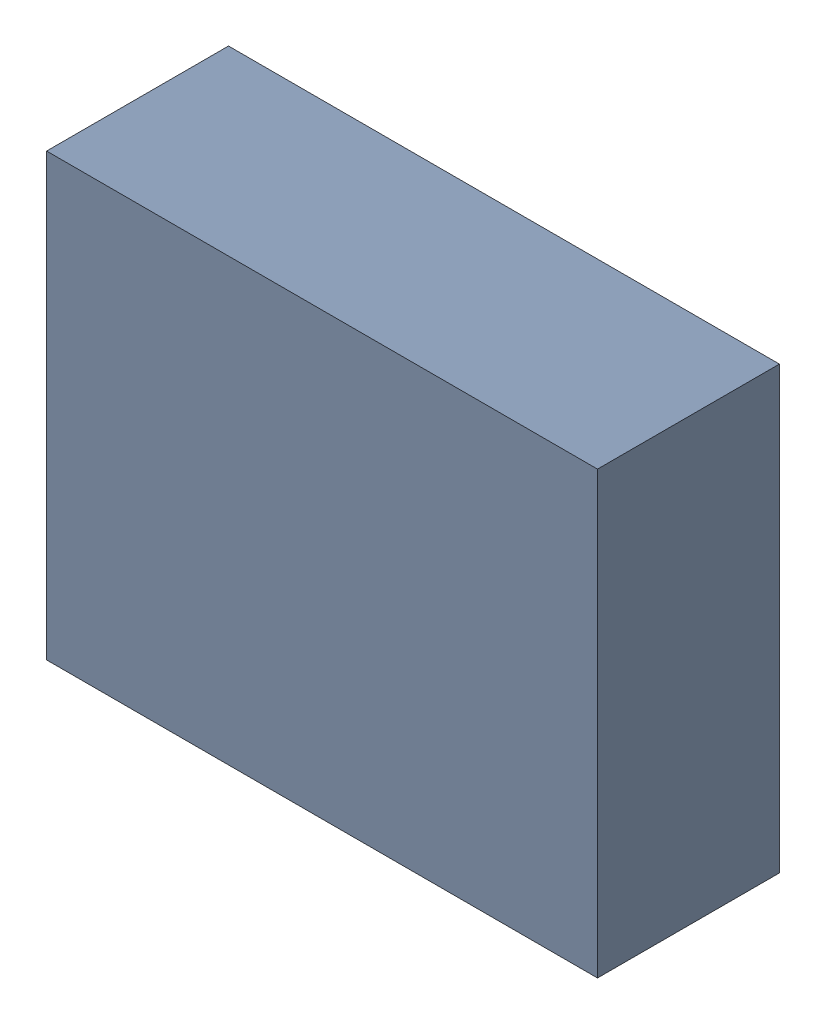
SolidWorks assembly USB01_U2, configuration Default. Lengths in mm.
Overall size (5 4 1.65).
2 component instances, 1 part files, 0 mates.
Components (placement in the parent):
- 402662544-1: 402662544 [Default] at (156.845 72.39 -2.8544) size (5 4 1.65)
  - Extruded_29-1: Extruded_29 [Default] at origin size (5 4 1.65)
